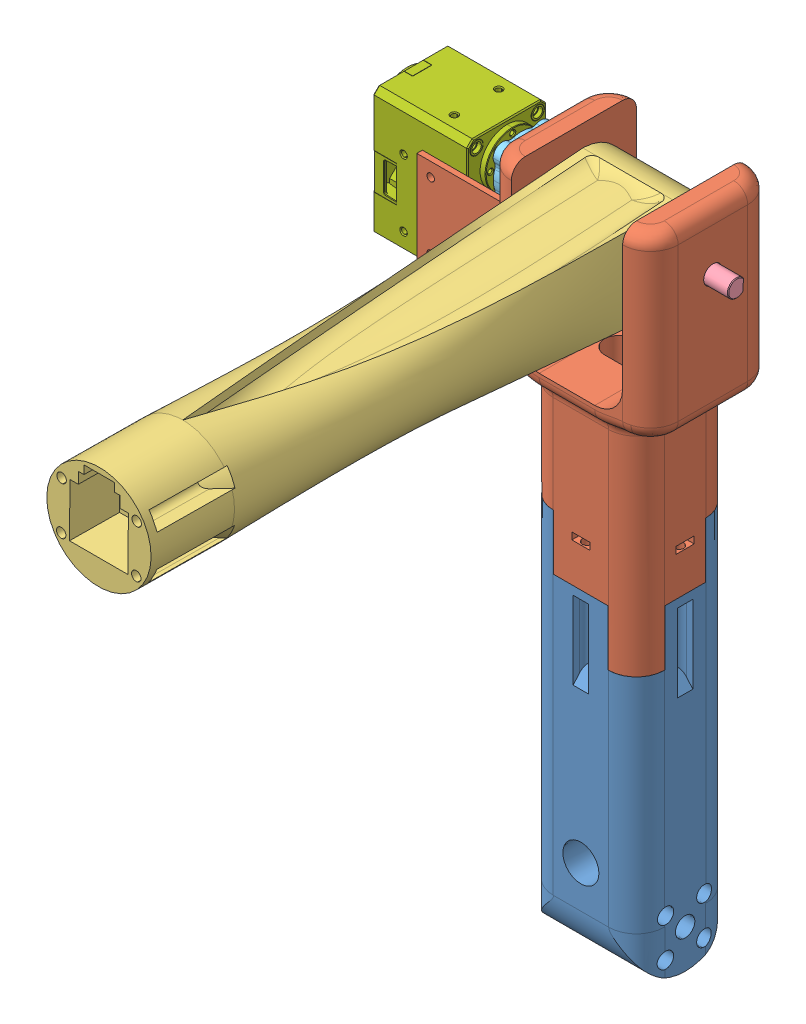
SolidWorks assembly Arm, configuration Default. Lengths in mm.
Overall size (118.6 242.5 213.47).
25 component instances, 7 part files, 30 mates.
Components (placement in the parent):
- Arm_1A-1: Arm_1A [Défaut] at origin size (42.86 137.5 35)
- Arm_1B-1: Arm_1B [Défaut] at (0 80 0) size (90 145 45)
- Arm_2-1: Arm_2 [Default] at (0 204.5 0) x (1 0 0) z (0 0.009406 0.999956) size (38.54 37.14 206.68)
- shaft-1: shaft [3po] at (0.5 204.5 0) x (0 0.999956 -0.009407) z (-1 0 0) size (6.35 5.71 76.2)
- 545548_hub-1: 545548_hub [Default] at (11.6615 165.6749 9.3366) x (0 -0.999956 0.009407) z (0 -0.009407 -0.999956) size (20.57 9.53 20.57)
  - 545548 assembly.STEP-1: 545548 assembly.STEP [Default] at origin size (20.57 9.53 20.57)
    - 545548.STEP-1: 545548.STEP [Default] at (-38.9112 12.0765 8.9709) size (20.57 9.53 20.57)
    - 632138_91375A438.STEP-1: 632138_91375A438.STEP [Default] at (-38.9112 18.109 15.0823) x (0.93363 0.358238 0) z (0 0 1) size (4.83 4.83 6.36)
- 545548_hub-2: 545548_hub [Default] at (-11.6615 243.4938 8.6045) x (0 0.999956 -0.009406) z (0 -0.009406 -0.999956) size (20.57 9.53 20.57)
  - 545548 assembly.STEP-1: 545548 assembly.STEP [Default] at origin size (20.57 9.53 20.57)
    - 545548.STEP-1: 545548.STEP [Default] at (-38.9112 12.0765 8.9709) size (20.57 9.53 20.57)
    - 632138_91375A438.STEP-1: 632138_91375A438.STEP [Default] at (-38.9112 18.109 15.0823) x (0.93363 0.358238 0) z (0 0 1) size (4.83 4.83 6.36)
- 545548_hub-3: 545548_hub [Default] at (10.8515 5.3711 38.9114) x (0 0 1) z (0 -1 0) size (20.57 9.53 20.57)
  - 545548 assembly.STEP-1: 545548 assembly.STEP [Default] at origin size (20.57 9.53 20.57)
    - 545548.STEP-1: 545548.STEP [Default] at (-38.9112 12.0765 8.9709) size (20.57 9.53 20.57)
    - 632138_91375A438.STEP-1: 632138_91375A438.STEP [Default] at (-38.9112 18.109 15.0823) x (0.93363 0.358238 0) z (0 0 1) size (4.83 4.83 6.36)
- 545548_hub-4: 545548_hub [Default] at (-10.8515 5.3707 -38.9114) x (0 0 -1) z (0 -1 0) size (20.57 9.53 20.57)
  - 545548 assembly.STEP-1: 545548 assembly.STEP [Default] at origin size (20.57 9.53 20.57)
    - 545548.STEP-1: 545548.STEP [Default] at (-38.9112 12.0765 8.9709) size (20.57 9.53 20.57)
    - 632138_91375A438.STEP-1: 632138_91375A438.STEP [Default] at (-38.9112 18.109 15.0823) x (0.93363 0.358238 0) z (0 0 1) size (4.83 4.83 6.36)
- XM430-W350-1: XM430-W350 [Default] at (-61 204.5 0) x (0 0 -1) z (1 0 0) size (28.5 46.5 42.4)
- 545548_hub-5: 545548_hub [Default] at (-17.2235 165.6749 9.3366) x (0 -0.999956 0.009407) z (0 -0.009407 -0.999956) size (20.57 9.53 20.57)
  - 545548 assembly.STEP-1: 545548 assembly.STEP [Default] at origin size (20.57 9.53 20.57)
    - 545548.STEP-1: 545548.STEP [Default] at (-38.9112 12.0765 8.9709) size (20.57 9.53 20.57)
    - 632138_91375A438.STEP-1: 632138_91375A438.STEP [Default] at (-38.9112 18.109 15.0823) x (0.93363 0.358238 0) z (0 0 1) size (4.83 4.83 6.36)
Mates (geometry in assembly coordinates):
- Coincident4: coincident anti-aligned: plane of Arm_1A-1 through (0 100 0) normal (0 1 0); plane of Arm_1B-1 through (0 100 0) normal (0 -1 0)
- Coincident6: coincident anti-aligned: plane of Arm_1A-1 through (9.8 80 17.5) normal (1 0 0); plane of Arm_1B-1 through (9.8 100 17.5) normal (-1 0 0)
- Coincident7: coincident anti-aligned: plane of Arm_1A-1 through (20 80 7.3) normal (0 0 1); plane of Arm_1B-1 through (9.8 100 7.3) normal (0 0 -1)
- Concentric1: concentric aligned: cylinder of Arm_1B-1 through (30 204.5 0) axis (-1 0 0) radius 3.35; cylinder of Arm_2-1 through (-19.966 204.5 0) axis (-1 0 0) radius 3.3734
- Coincident8: coincident aligned: plane of Arm_1B-1 through (0 80 0) normal (1 0 0); plane of Arm_2-1 through (0 204.5 0) normal (1 0 0)
- Concentric5: concentric aligned: cylinder of Arm_1B-1 through (30 204.5 0) axis (-1 0 0) radius 3.35; cylinder of XM430-W350-1 through (-39.65 204.5 0) axis (-1 0 0) radius 4
- Concentric6: concentric anti-aligned: cylinder of Arm_1B-1 through (-55 200.5 -22.5) axis (0 0 1) radius 1.35; cylinder of XM430-W350-1 through (-55 200.5 10.4533) axis (0 0 -1) radius 1.025
- Concentric8: concentric anti-aligned: cylinder of Arm_2-1 through (-19.966 204.5 0) axis (-1 0 0) radius 3.3734; cylinder of shaft-1 through (-37.6 204.5 0) axis (1 0 0) radius 3.175
- Coincident12: coincident anti-aligned: plane of XM430-W350-1 through (-37.6 204.5 0) normal (1 0 0); plane of shaft-1 through (-37.6 204.5 0) normal (-1 0 0)
- Concentric10: concentric anti-aligned: cylinder of 545548_hub-1/545548 assembly.STEP-1/545548.STEP-1 through (-9.94 204.5 0) axis (-1 0 0) radius 3.175; cylinder of shaft-1 through (-37.6 204.5 0) axis (1 0 0) radius 3.175
- Coincident13: coincident anti-aligned: plane of Arm_2-1 through (-9.94 214.3079 -5.5257) normal (1 0 0); plane of 545548_hub-1/545548 assembly.STEP-1/545548.STEP-1 through (-9.94 207.9898 3.4247) normal (-1 0 0)
- Concentric11: concentric aligned: cylinder of Arm_2-1 through (-19.966 197.5205 -6.8494) axis (-1 0 0) radius 2.75; circle of 545548_hub-1/545548 assembly.STEP-1/545548.STEP-1
- Coincident14: coincident aligned: plane of Arm_1A-1 through (0 0 0) normal (0 0 1)
- Coincident15: coincident aligned: plane of Arm_1A-1 through (0 0 0) normal (0 1 0)
- Coincident16: coincident aligned: plane of Arm_1A-1 through (0 0 0) normal (1 0 0)
- Parallel1: parallel aligned: plane of shaft-1 through (-37.6 206.381 -2.5578) normal (0 -0.009407 -0.999956); plane of 545548_hub-1/545548 assembly.STEP-1/632138_91375A438.STEP-1 through (-7.5158 203.5651 -7.3924) normal (0 -0.009407 -0.999956)
- Concentric12: concentric aligned: cylinder of shaft-1 through (-37.6 204.5 0) axis (1 0 0) radius 3.175; cylinder of 545548_hub-2/545548 assembly.STEP-1/545548.STEP-1 through (9.94 204.5 0) axis (1 0 0) radius 3.175
- Concentric13: concentric aligned: cylinder of Arm_2-1 through (19.272 211.3495 -6.9795) axis (-1 0 0) radius 2.75; circle of 545548_hub-2/545548 assembly.STEP-1/545548.STEP-1
- Coincident18: coincident anti-aligned: plane of Arm_2-1 through (9.94 214.3079 -5.5257) normal (-1 0 0); plane of 545548_hub-2/545548 assembly.STEP-1/545548.STEP-1 through (9.94 201.0753 3.4898) normal (1 0 0)
- Concentric14: concentric anti-aligned: cylinder of Arm_1A-1 through (20 -3.6 0) axis (1 0 0) radius 3.5; cylinder of 545548_hub-3/545548 assembly.STEP-1/545548.STEP-1 through (-10.75 -3.5998 0.0002) axis (-1 0 0) radius 3.175
- Concentric15: concentric anti-aligned: cylinder of Arm_1A-1 through (20 3.315 6.915) axis (1 0 0) radius 2.8; circle of 545548_hub-3/545548 assembly.STEP-1/545548.STEP-1
- Coincident19: coincident anti-aligned: plane of Arm_1A-1 through (-10.75 7.5 11) normal (1 0 0); plane of 545548_hub-3/545548 assembly.STEP-1/545548.STEP-1 through (-10.75 -0.1424 -3.4572) normal (-1 0 0)
- Concentric16: concentric aligned: cylinder of Arm_1A-1 through (20 -3.6 0) axis (1 0 0) radius 3.5; cylinder of 545548_hub-4/545548 assembly.STEP-1/545548.STEP-1 through (10.75 -3.6002 -0.0002) axis (1 0 0) radius 3.175
- Concentric17: concentric anti-aligned: cylinder of Arm_1A-1 through (20 -10.515 -6.915) axis (1 0 0) radius 2.8; circle of 545548_hub-4/545548 assembly.STEP-1/545548.STEP-1
- Coincident20: coincident anti-aligned: plane of Arm_1A-1 through (10.75 7.5 11) normal (-1 0 0); plane of 545548_hub-4/545548 assembly.STEP-1/545548.STEP-1 through (10.75 -0.1428 3.4572) normal (1 0 0)
- Coincident21: coincident anti-aligned: plane of shaft-1 through (-37.6 204.5 0) normal (-1 0 0); plane of XM430-W350-1 through (-37.6 204.5 0) normal (1 0 0)
- Concentric18: concentric anti-aligned: cylinder of Arm_1B-1 through (-55 200.5 -22.5) axis (0 0 1) radius 1.35; cylinder of XM430-W350-1 through (-55 200.5 10.4533) axis (0 0 -1) radius 1.025
- Concentric20: concentric anti-aligned: cylinder of shaft-1 through (-37.6 204.5 0) axis (1 0 0) radius 3.175; cylinder of 545548_hub-5/545548 assembly.STEP-1/545548.STEP-1 through (-38.825 204.5 0) axis (-1 0 0) radius 3.175
- Parallel3: parallel aligned: plane of shaft-1 through (-37.6 206.381 -2.5578) normal (0 -0.009407 -0.999956); plane of 545548_hub-5/545548 assembly.STEP-1/632138_91375A438.STEP-1 through (-36.4008 203.5651 -7.3924) normal (0 -0.009407 -0.999956)
- Distance1: distance = 3.175 mm anti-aligned: plane of 545548_hub-5/545548 assembly.STEP-1/545548.STEP-1 through (-38.825 207.9898 3.4247) normal (-1 0 0); plane of XM430-W350-1 through (-42 204.5 0) normal (1 0 0)
